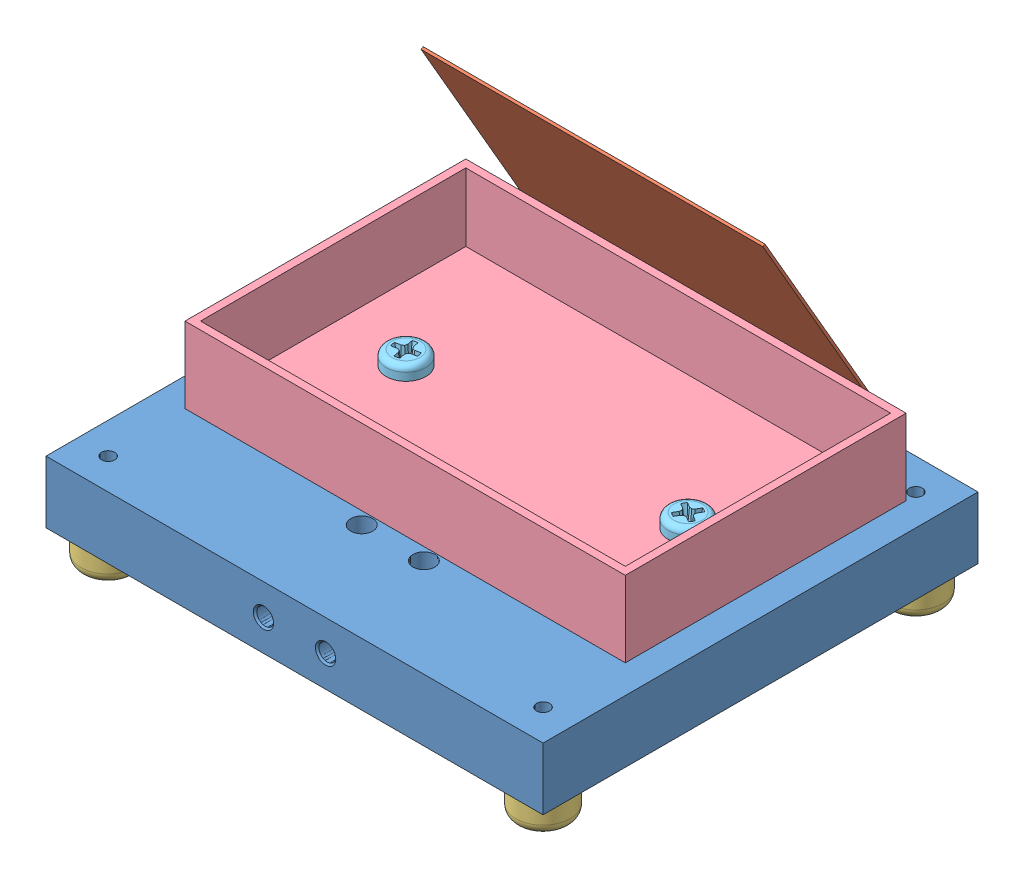
SolidWorks assembly Base_assy, configuration Default. Lengths in mm.
Overall size (103.02 68.83 92.65).
11 component instances, 6 part files, 34 mates.
Components (placement in the parent):
- Base-1: Base [Default] at (101.6 22.2369 0) x (1 0 0) z (0 -1 0) size (101.6 88.9 12.7)
- Plate-1: Plate [Default] at (85.725 22.2369 -0.508) x (0 1 0) z (1 0 0) size (62.48 28.61 69.85)
- 9541K800_BUMPER WITH THREADED STUD_new-1: 9541K800_BUMPER WITH THREADED STUD_new [9541K8] at (6.35 9.5369 6.35) x (-0.997902 0 0.064746) z (0.064746 0 0.997902) size (11.11 12.97 11.11)
- 9541K800_BUMPER WITH THREADED STUD_new-2: 9541K800_BUMPER WITH THREADED STUD_new [9541K8] at (6.35 9.5369 82.55) x (-0.985271 0 -0.170998) z (-0.170998 0 0.985271) size (11.11 12.97 11.11)
- 9541K800_BUMPER WITH THREADED STUD_new-3: 9541K800_BUMPER WITH THREADED STUD_new [9541K8] at (95.25 9.5369 6.35) x (-0.837169 0 -0.546944) z (-0.546944 0 0.837169) size (11.11 12.97 11.11)
- 9541K800_BUMPER WITH THREADED STUD_new-4: 9541K800_BUMPER WITH THREADED STUD_new [9541K8] at (95.25 9.5369 82.55) x (-0.925243 0 -0.379375) z (-0.379375 0 0.925243) size (11.11 12.97 11.11)
- 1155_battery_holder-1: 1155_battery_holder [Default] at (95.8 22.2369 8.89) x (0 0 1) z (-1 0 0) size (57.4 15.49 90)
- 8_32_500_nylon_93135A353-1: 8_32_500_nylon_93135A353 [93135A353] at (79.925 23.8244 37.592) x (0.857399 0 0.514652) z (0 1 0) size (8.13 8.13 15.77)
- 8_32_500_nylon_93135A353-2: 8_32_500_nylon_93135A353 [93135A353] at (22.2797 23.8244 37.592) x (0.982082 0 -0.188455) z (0 1 0) size (8.13 8.13 15.77)
- 8_32-750_stainless_92949A197-1: 8_32-750_stainless_92949A197 [92949A197] at (76.2 15.8869 -2.7178) x (-0.923728 -0.383049 0) z (0 0 -1) size (7.92 7.92 21.73)
- 8_32-750_stainless_92949A197-2: 8_32-750_stainless_92949A197 [92949A197] at (25.4 15.8869 -2.7178) x (-0.923728 -0.383049 0) z (0 0 -1) size (7.92 7.92 21.73)
Mates (geometry in assembly coordinates):
- Coincident16: coincident anti-aligned: plane of Base-1 through (101.6 9.5369 0) normal (0 -1 0); plane of 9541K800_BUMPER WITH THREADED STUD_new-1 through (2.0706 9.5369 6.6277) normal (0 1 0)
- Concentric18: concentric aligned: cylinder of Base-1 through (6.35 9.5369 6.35) axis (0 -1 0) radius 1.3526; cylinder of 9541K800_BUMPER WITH THREADED STUD_new-1 through (6.35 3.1869 6.35) axis (0 -1 0) radius 5.5563
- Coincident15: coincident anti-aligned: plane of Base-1 through (101.6 9.5369 0) normal (0 -1 0); plane of 9541K800_BUMPER WITH THREADED STUD_new-2 through (2.1248 9.5369 81.8167) normal (0 1 0)
- Concentric17: concentric aligned: cylinder of Base-1 through (6.35 9.5369 82.55) axis (0 -1 0) radius 1.3526; cylinder of 9541K800_BUMPER WITH THREADED STUD_new-2 through (6.35 3.1869 82.55) axis (0 -1 0) radius 5.5563
- Coincident42: coincident anti-aligned: plane of Base-1 through (101.6 9.5369 0) normal (0 -1 0); plane of 9541K800_BUMPER WITH THREADED STUD_new-3 through (91.6599 9.5369 4.0045) normal (0 1 0)
- Concentric39: concentric aligned: cylinder of Base-1 through (95.25 9.5369 6.35) axis (0 -1 0) radius 1.3526; cylinder of 9541K800_BUMPER WITH THREADED STUD_new-3 through (95.25 3.1869 6.35) axis (0 -1 0) radius 5.5563
- Coincident43: coincident anti-aligned: plane of Base-1 through (101.6 9.5369 0) normal (0 -1 0); plane of 9541K800_BUMPER WITH THREADED STUD_new-4 through (91.2822 9.5369 80.9231) normal (0 1 0)
- Concentric40: concentric aligned: cylinder of Base-1 through (95.25 9.5369 82.55) axis (0 -1 0) radius 1.3526; cylinder of 9541K800_BUMPER WITH THREADED STUD_new-4 through (95.25 3.1869 82.55) axis (0 -1 0) radius 5.5563
- Concentric41: concentric aligned: cylinder of ? through (17.4625 25.6067 6.35) axis (0 -1 0) radius 4.064; cylinder of Base-1 through (17.4625 9.5369 6.35) axis (0 -1 0) radius 1.7272
- Concentric44: concentric aligned: cylinder of Base-1 through (84.1375 9.5369 6.35) axis (0 -1 0) radius 1.7272; cylinder of ? through (84.1375 27.5709 6.35) axis (0 -1 0) radius 4.064
- Coincident59: coincident anti-aligned: plane of ? through (84.1375 24.7769 6.35) normal (0 1 0); plane of ? through (84.1375 24.7769 6.35) normal (0 -1 0)
- Coincident61: coincident anti-aligned: plane of ? through (17.4625 24.7769 6.35) normal (0 -1 0); plane of ? through (17.4625 24.7769 6.35) normal (0 1 0)
- Width2: width anti-aligned: plane of Plate-1 through (85.725 22.2369 0) normal (1 0 0); plane of Plate-1 through (15.875 22.2369 0) normal (-1 0 0); plane of Base-1 through (0 9.5369 0) normal (-1 0 0); plane of Base-1 through (101.6 9.5369 0) normal (1 0 0)
- Distance2: distance = 8.89 mm aligned: plane of Base-1 through (101.6 9.5369 0) normal (0 0 -1); plane of 1155_battery_holder-1 through (95.8 23.8244 8.89) normal (0 0 -1)
- Width3: width anti-aligned: plane of Base-1 through (0 9.5369 0) normal (-1 0 0); plane of Base-1 through (101.6 9.5369 0) normal (1 0 0); plane of 1155_battery_holder-1 through (95.8 23.8244 8.89) normal (1 0 0); plane of 1155_battery_holder-1 through (5.8 23.8244 8.89) normal (-1 0 0)
- Coincident65: coincident anti-aligned: plane of Base-1 through (101.6 22.2369 0) normal (0 1 0); plane of ? through (22.2797 22.2369 36.6395) normal (0 -1 0)
- Coincident66: coincident anti-aligned: plane of 1155_battery_holder-1 through (95.8 23.8244 8.89) normal (0 1 0); plane of 8_32_500_nylon_93135A353-1 through (79.925 23.8244 37.592) normal (0 -1 0)
- Concentric55: concentric anti-aligned: cylinder of 1155_battery_holder-1 through (79.925 23.8244 37.592) axis (0 1 0) radius 2.2479; cylinder of 8_32_500_nylon_93135A353-1 through (79.925 26.6184 37.592) axis (0 -1 0) radius 4.064
- Coincident67: coincident anti-aligned: plane of 1155_battery_holder-1 through (95.8 23.8244 8.89) normal (0 1 0); plane of 8_32_500_nylon_93135A353-2 through (22.2797 23.8244 37.592) normal (0 -1 0)
- Concentric56: concentric anti-aligned: cylinder of 1155_battery_holder-1 through (22.2797 23.8244 37.592) axis (0 1 0) radius 2.2479; cylinder of 8_32_500_nylon_93135A353-2 through (22.2797 26.6184 37.592) axis (0 -1 0) radius 4.064
- Concentric57: concentric aligned: cylinder of ? through (17.4625 27.5709 6.35) axis (0 -1 0) radius 4.064; circle of ?
- Concentric58: concentric aligned: cylinder of ? through (17.4625 27.5709 6.35) axis (0 -1 0) radius 4.064; circle of ?
- Coincident69: coincident anti-aligned: plane of ? through (17.4625 23.7609 6.35) normal (0 1 0); plane of ? through (17.4625 23.7609 6.35) normal (0 -1 0)
- Concentric59: concentric aligned: cylinder of ? through (84.1375 27.5709 6.35) axis (0 -1 0) radius 4.064; circle of ?
- Concentric60: concentric aligned: cylinder of ? through (84.1375 27.5709 6.35) axis (0 -1 0) radius 4.064; circle of ?
- Coincident71: coincident anti-aligned: plane of ? through (84.1375 23.7609 6.35) normal (0 1 0); plane of ? through (84.1375 23.7609 6.35) normal (0 -1 0)
- Coincident72: coincident anti-aligned: plane of Base-1 through (101.6 22.2369 0) normal (0 1 0); plane of 1155_battery_holder-1 through (95.8 22.2369 8.89) normal (0 -1 0)
- Coincident73: coincident anti-aligned: plane of Base-1 through (101.6 9.5369 0) normal (0 0 -1); plane of Plate-1 through (85.725 22.2369 0) normal (0 0 1)
- Concentric61: concentric aligned: cylinder of Base-1 through (76.2 15.8869 0) axis (0 0 -1) radius 1.7272; cylinder of Plate-1 through (76.2 15.8869 -0.508) axis (0 0 -1) radius 2.2479
- Concentric62: concentric anti-aligned: cylinder of Base-1 through (76.2 15.8869 0) axis (0 0 -1) radius 1.7272; cylinder of ? through (76.2 15.8869 -3.302) axis (0 0 1) radius 4.064
- Coincident75: coincident anti-aligned: plane of Plate-1 through (85.725 22.2369 -0.508) normal (0 0 -1); plane of 8_32-750_stainless_92949A197-2 through (26.9178 12.2268 -0.508) normal (0 0 1)
- Concentric63: concentric aligned: cylinder of Base-1 through (25.4 15.8869 0) axis (0 0 -1) radius 1.7272; cylinder of 8_32-750_stainless_92949A197-2 through (25.4 15.8869 -2.7178) axis (0 0 -1) radius 3.9624
- Coincident76: coincident anti-aligned: plane of Plate-1 through (85.725 22.2369 -0.508) normal (0 0 -1); plane of 8_32-750_stainless_92949A197-1 through (77.7178 12.2268 -0.508) normal (0 0 1)
- Concentric64: concentric aligned: cylinder of Base-1 through (76.2 15.8869 0) axis (0 0 -1) radius 1.7272; cylinder of 8_32-750_stainless_92949A197-1 through (76.2 15.8869 -2.7178) axis (0 0 -1) radius 3.9624
